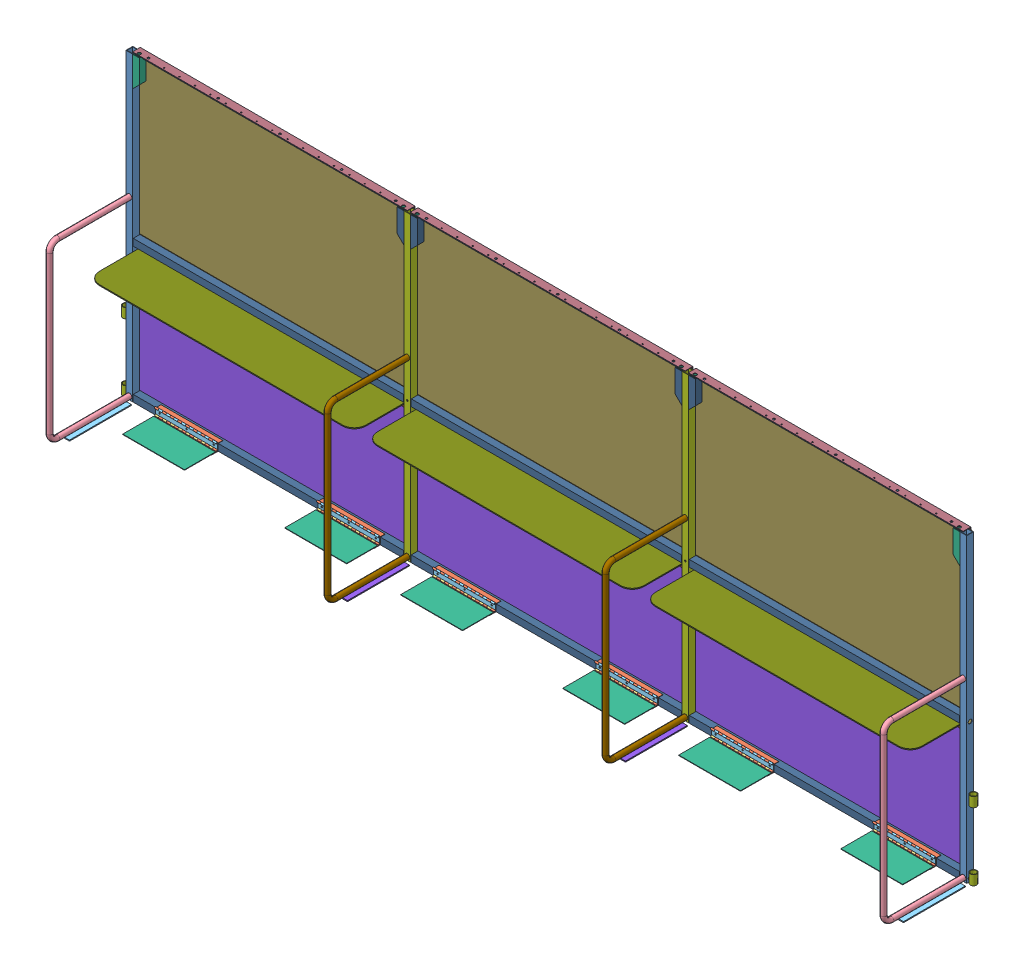
SolidWorks assembly FE-00038-01_ASM, configuration Default. Lengths in mm.
Overall size (5615.18 1984.41 604.9).
184 component instances, 33 part files, 0 mates.
Components (placement in the parent):
- FE-00002-L_ASM-1: FE-00002-L_ASM [Default] at origin size (175.51 1981.23 585.85)
  - FE-00002-05-1: FE-00002-05 [Default] at origin size (44.45 1981.2 44.45)
  - FE-00002-01-1: FE-00002-01 [Default] at (3.175 22.225 -22.225) size (130.18 36.51 36.51)
  - FE-00002-02-1: FE-00002-02 [Default] at (3.175 911.225 -22.225) size (120.65 36.51 36.51)
  - FE-00002-06-1: FE-00002-06 [Default] at (22.225 23.0188 0) x (1 0 0) z (0 0 -1) size (33.4 1168.46 541.4)
  - FE-00002-07-1: FE-00002-07 [Default] at (60.325 6.3182 25.4) x (0 0 1) z (1 0 0) size (406.4 6.35 76.2)
  - FE-00002-03-1: FE-00002-03 [Default] at (44.45 1981.2 0) x (0 0 -1) z (-1 0 0) size (44.45 196.85 44.45)
  - FE-00002-09-1: FE-00002-09 [Default] at (-21.082 31.75 -21.1582) size (42.16 63.5 42.16)
  - FE-00002-09-2: FE-00002-09 [Default] at (-21.082 476.25 -21.1582) size (42.16 63.5 42.16)
- FE-00004_ASM-1: FE-00004_ASM [Default] at (936.625 0 -49.2125) size (1828.8 933.45 374.65)
  - FE-00004-01-1: FE-00004-01 [Default] at origin size (1828.8 914.4 4.76)
  - FE-00004-05-1: FE-00004-05 [Default] at (0 914.4 -4.7625) x (1 0 0) z (0 -1 0) size (1828.8 19.05 19.05)
  - FE-00004-04-1: FE-00004-04 [Default] at (0 911.225 26.9875) size (1778 44.45 44.45)
  - FE-00004-04-2: FE-00004-04 [Default] at (0 22.225 26.9875) size (1778 44.45 44.45)
  - FE-00004-02_ASM-1: FE-00004-02_ASM [Default] at (-647.7 858.139 4.7625) x (-1 0 0) z (0 0 -1) size (406.4 43.56 43.56)
    - FE-00004-02-A-1: FE-00004-02-A [Default] at origin size (406.4 43.56 10.92)
    - FE-00004-02-A-2: FE-00004-02-A [Default] at (0 5.461 -5.461) x (-1 0 0) z (0 1 0) size (406.4 43.56 10.92)
    - FE-00004-02-B-1: FE-00004-02-B [Default] at (0 0 -5.461) size (406.4 6.35 6.35)
  - FE-00004-02_ASM-2: FE-00004-02_ASM [Default] at (647.7 858.139 4.7625) x (-1 0 0) z (0 0 -1) size (406.4 43.56 43.56)
    - FE-00004-02-A-1: FE-00004-02-A [Default] at origin size (406.4 43.56 10.92)
    - FE-00004-02-A-2: FE-00004-02-A [Default] at (0 5.461 -5.461) x (-1 0 0) z (0 1 0) size (406.4 43.56 10.92)
    - FE-00004-02-B-1: FE-00004-02-B [Default] at (0 0 -5.461) size (406.4 6.35 6.35)
  - FE-00004-03_ASM-1: FE-00004-03_ASM [Default] at (0 863.6 10.2235) x (1 0 0) z (0 1 0) size (482.6 43.56 43.56)
    - FE-00004-03-A-1: FE-00004-03-A [Default] at origin size (482.6 43.56 10.92)
    - FE-00004-03-B-1: FE-00004-03-B [Default] at (0 5.461 -5.461) x (-1 0 0) z (0 1 0) size (482.6 43.56 10.92)
    - FE-00004-03-C-1: FE-00004-03-C [Default] at (0 0 -5.461) size (482.6 6.35 6.35)
  - FE-00004-06-1: FE-00004-06 [Default] at (127 863.6 182.5625) size (1752.6 6.35 355.6)
  - FE-00004-09-1: FE-00004-09 [Default] at (-403.9235 787.4 155.2839) x (1 0 0) z (0 -1 0) size (3.18 302.13 152.4)
  - FE-00004-08_ASM-1: FE-00004-08_ASM [Default] at (-400.7485 858.139 179.8901) x (0 0 1) z (-1 0 0) size (203.2 43.56 43.56)
    - FE-00004-08-A-1: FE-00004-08-A [Default] at origin size (203.2 43.56 10.92)
    - FE-00004-08-A-2: FE-00004-08-A [Default] at (0 5.461 -5.461) x (-1 0 0) z (0 1 0) size (203.2 43.56 10.92)
    - FE-00004-08-C-1: FE-00004-08-C [Default] at (0 0 -5.461) size (203.2 6.35 6.35)
  - FE-00004-09-2: FE-00004-09 [Default] at (400.7485 787.4 155.2839) x (1 0 0) z (0 -1 0) size (3.18 302.13 152.4)
  - FE-00004-08_ASM-2: FE-00004-08_ASM [Default] at (400.7485 858.139 179.8901) x (0 0 -1) z (1 0 0) size (203.2 43.56 43.56)
    - FE-00004-08-A-1: FE-00004-08-A [Default] at origin size (203.2 43.56 10.92)
    - FE-00004-08-A-2: FE-00004-08-A [Default] at (0 5.461 -5.461) x (-1 0 0) z (0 1 0) size (203.2 43.56 10.92)
    - FE-00004-08-C-1: FE-00004-08-C [Default] at (0 0 -5.461) size (203.2 6.35 6.35)
  - FE-00004-07_ASM-1: FE-00004-07_ASM [Default] at (-533.4 0 54.6735) x (-1 0 0) z (0 -1 0) size (406.4 73.91 55.37)
    - FE-00004-07-A-1: FE-00004-07-A [Default] at origin size (406.4 43.56 10.92)
    - FE-00004-07-A_AF0-1: FE-00004-07-A_AF0 [Default] at (0 5.461 -5.461) x (-1 0 0) z (0 1 0) size (406.4 43.56 10.92)
    - FE-00004-07-B-1: FE-00004-07-B [Default] at (0 0 -5.461) size (406.4 6.35 6.35)
    - FE-00004-07-A_AF1-1: FE-00004-07-A_AF1 [Default] at (0 3.175 -49.911) x (1 0 0) z (0 1 0) size (406.4 43.56 10.92)
    - FE-00004-07-A-2: FE-00004-07-A [Default] at (0 -2.286 -44.45) x (-1 0 0) z (0 0 1) size (406.4 43.56 10.92)
    - FE-00004-07-B-2: FE-00004-07-B [Default] at (0 -2.286 -49.911) size (406.4 6.35 6.35)
  - FE-00004-07_ASM-2: FE-00004-07_ASM [Default] at (533.4 0 54.6735) x (-1 0 0) z (0 -1 0) size (406.4 73.91 55.37)
    - FE-00004-07-A-1: FE-00004-07-A [Default] at origin size (406.4 43.56 10.92)
    - FE-00004-07-A_AF0-1: FE-00004-07-A_AF0 [Default] at (0 5.461 -5.461) x (-1 0 0) z (0 1 0) size (406.4 43.56 10.92)
    - FE-00004-07-B-1: FE-00004-07-B [Default] at (0 0 -5.461) size (406.4 6.35 6.35)
    - FE-00004-07-A_AF1-1: FE-00004-07-A_AF1 [Default] at (0 3.175 -49.911) x (1 0 0) z (0 1 0) size (406.4 43.56 10.92)
    - FE-00004-07-A-2: FE-00004-07-A [Default] at (0 -2.286 -44.45) x (-1 0 0) z (0 0 1) size (406.4 43.56 10.92)
    - FE-00004-07-B-2: FE-00004-07-B [Default] at (0 -2.286 -49.911) size (406.4 6.35 6.35)
  - FE-00004-10-1: FE-00004-10 [Default] at (-533.4 2.286 168.9735) size (406.4 3.17 203.2)
  - FE-00004-10-2: FE-00004-10 [Default] at (533.4 2.286 168.9735) size (406.4 3.17 203.2)
- FE-00001_ASM-1: FE-00001_ASM [Default] at (1873.25 0 -44.45) x (-1 0 0) z (0 0 -1) size (209.55 1981.2 585.85)
  - FE-00001-05-1: FE-00001-05 [Default] at origin size (44.45 1981.2 44.45)
  - FE-00001-02-1: FE-00001-02 [Default] at (60.325 0 -69.85) x (0 0 -1) z (1 0 0) size (406.4 6.35 76.2)
  - FE-00001-03-1: FE-00001-03 [Default] at (22.225 1158.113 -44.45) size (33.4 1168.46 541.4)
  - FE-00001-01-1: FE-00001-01 [Default] at (44.45 1981.2 0) x (0 0 -1) z (-1 0 0) size (44.45 196.85 44.45)
  - FE-00001-01-2: FE-00001-01 [Default] at (0 1981.2 -44.45) x (0 0 1) z (1 0 0) size (44.45 196.85 44.45)
  - FE-00001-04-1: FE-00001-04 [Default] at (-82.55 22.225 -22.225) size (203.2 36.51 36.51)
  - FE-00001-04-2: FE-00001-04 [Default] at (-76.2 911.225 -22.225) size (203.2 36.51 36.51)
- FE-00004_ASM-2: FE-00004_ASM [Default] at (2765.425 0 -49.2125) size (1828.8 933.45 374.65)
  - FE-00004-01-1: FE-00004-01 [Default] at origin size (1828.8 914.4 4.76)
  - FE-00004-05-1: FE-00004-05 [Default] at (0 914.4 -4.7625) x (1 0 0) z (0 -1 0) size (1828.8 19.05 19.05)
  - FE-00004-04-1: FE-00004-04 [Default] at (0 911.225 26.9875) size (1778 44.45 44.45)
  - FE-00004-04-2: FE-00004-04 [Default] at (0 22.225 26.9875) size (1778 44.45 44.45)
  - FE-00004-02_ASM-1: FE-00004-02_ASM [Default] at (-647.7 858.139 4.7625) x (-1 0 0) z (0 0 -1) size (406.4 43.56 43.56)
    - FE-00004-02-A-1: FE-00004-02-A [Default] at origin size (406.4 43.56 10.92)
    - FE-00004-02-A-2: FE-00004-02-A [Default] at (0 5.461 -5.461) x (-1 0 0) z (0 1 0) size (406.4 43.56 10.92)
    - FE-00004-02-B-1: FE-00004-02-B [Default] at (0 0 -5.461) size (406.4 6.35 6.35)
  - FE-00004-02_ASM-2: FE-00004-02_ASM [Default] at (647.7 858.139 4.7625) x (-1 0 0) z (0 0 -1) size (406.4 43.56 43.56)
    - FE-00004-02-A-1: FE-00004-02-A [Default] at origin size (406.4 43.56 10.92)
    - FE-00004-02-A-2: FE-00004-02-A [Default] at (0 5.461 -5.461) x (-1 0 0) z (0 1 0) size (406.4 43.56 10.92)
    - FE-00004-02-B-1: FE-00004-02-B [Default] at (0 0 -5.461) size (406.4 6.35 6.35)
  - FE-00004-03_ASM-1: FE-00004-03_ASM [Default] at (0 863.6 10.2235) x (1 0 0) z (0 1 0) size (482.6 43.56 43.56)
    - FE-00004-03-A-1: FE-00004-03-A [Default] at origin size (482.6 43.56 10.92)
    - FE-00004-03-B-1: FE-00004-03-B [Default] at (0 5.461 -5.461) x (-1 0 0) z (0 1 0) size (482.6 43.56 10.92)
    - FE-00004-03-C-1: FE-00004-03-C [Default] at (0 0 -5.461) size (482.6 6.35 6.35)
  - FE-00004-06-1: FE-00004-06 [Default] at (127 863.6 182.5625) size (1752.6 6.35 355.6)
  - FE-00004-09-1: FE-00004-09 [Default] at (-403.9235 787.4 155.2839) x (1 0 0) z (0 -1 0) size (3.18 302.13 152.4)
  - FE-00004-08_ASM-1: FE-00004-08_ASM [Default] at (-400.7485 858.139 179.8901) x (0 0 1) z (-1 0 0) size (203.2 43.56 43.56)
    - FE-00004-08-A-1: FE-00004-08-A [Default] at origin size (203.2 43.56 10.92)
    - FE-00004-08-A-2: FE-00004-08-A [Default] at (0 5.461 -5.461) x (-1 0 0) z (0 1 0) size (203.2 43.56 10.92)
    - FE-00004-08-C-1: FE-00004-08-C [Default] at (0 0 -5.461) size (203.2 6.35 6.35)
  - FE-00004-09-2: FE-00004-09 [Default] at (400.7485 787.4 155.2839) x (1 0 0) z (0 -1 0) size (3.18 302.13 152.4)
  - FE-00004-08_ASM-2: FE-00004-08_ASM [Default] at (400.7485 858.139 179.8901) x (0 0 -1) z (1 0 0) size (203.2 43.56 43.56)
    - FE-00004-08-A-1: FE-00004-08-A [Default] at origin size (203.2 43.56 10.92)
    - FE-00004-08-A-2: FE-00004-08-A [Default] at (0 5.461 -5.461) x (-1 0 0) z (0 1 0) size (203.2 43.56 10.92)
    - FE-00004-08-C-1: FE-00004-08-C [Default] at (0 0 -5.461) size (203.2 6.35 6.35)
  - FE-00004-07_ASM-1: FE-00004-07_ASM [Default] at (-533.4 0 54.6735) x (-1 0 0) z (0 -1 0) size (406.4 73.91 55.37)
    - FE-00004-07-A-1: FE-00004-07-A [Default] at origin size (406.4 43.56 10.92)
    - FE-00004-07-A_AF0-1: FE-00004-07-A_AF0 [Default] at (0 5.461 -5.461) x (-1 0 0) z (0 1 0) size (406.4 43.56 10.92)
    - FE-00004-07-B-1: FE-00004-07-B [Default] at (0 0 -5.461) size (406.4 6.35 6.35)
    - FE-00004-07-A_AF1-1: FE-00004-07-A_AF1 [Default] at (0 3.175 -49.911) x (1 0 0) z (0 1 0) size (406.4 43.56 10.92)
    - FE-00004-07-A-2: FE-00004-07-A [Default] at (0 -2.286 -44.45) x (-1 0 0) z (0 0 1) size (406.4 43.56 10.92)
    - FE-00004-07-B-2: FE-00004-07-B [Default] at (0 -2.286 -49.911) size (406.4 6.35 6.35)
  - FE-00004-07_ASM-2: FE-00004-07_ASM [Default] at (533.4 0 54.6735) x (-1 0 0) z (0 -1 0) size (406.4 73.91 55.37)
    - FE-00004-07-A-1: FE-00004-07-A [Default] at origin size (406.4 43.56 10.92)
    - FE-00004-07-A_AF0-1: FE-00004-07-A_AF0 [Default] at (0 5.461 -5.461) x (-1 0 0) z (0 1 0) size (406.4 43.56 10.92)
    - FE-00004-07-B-1: FE-00004-07-B [Default] at (0 0 -5.461) size (406.4 6.35 6.35)
    - FE-00004-07-A_AF1-1: FE-00004-07-A_AF1 [Default] at (0 3.175 -49.911) x (1 0 0) z (0 1 0) size (406.4 43.56 10.92)
    - FE-00004-07-A-2: FE-00004-07-A [Default] at (0 -2.286 -44.45) x (-1 0 0) z (0 0 1) size (406.4 43.56 10.92)
    - FE-00004-07-B-2: FE-00004-07-B [Default] at (0 -2.286 -49.911) size (406.4 6.35 6.35)
  - FE-00004-10-1: FE-00004-10 [Default] at (-533.4 2.286 168.9735) size (406.4 3.17 203.2)
  - FE-00004-10-2: FE-00004-10 [Default] at (533.4 2.286 168.9735) size (406.4 3.17 203.2)
- FE-00001_ASM-2: FE-00001_ASM [Default] at (3702.05 0 -44.45) x (-1 0 0) z (0 0 -1) size (209.55 1981.2 585.85)
  - FE-00001-05-1: FE-00001-05 [Default] at origin size (44.45 1981.2 44.45)
  - FE-00001-02-1: FE-00001-02 [Default] at (60.325 0 -69.85) x (0 0 -1) z (1 0 0) size (406.4 6.35 76.2)
  - FE-00001-03-1: FE-00001-03 [Default] at (22.225 1158.113 -44.45) size (33.4 1168.46 541.4)
  - FE-00001-01-1: FE-00001-01 [Default] at (44.45 1981.2 0) x (0 0 -1) z (-1 0 0) size (44.45 196.85 44.45)
  - FE-00001-01-2: FE-00001-01 [Default] at (0 1981.2 -44.45) x (0 0 1) z (1 0 0) size (44.45 196.85 44.45)
  - FE-00001-04-1: FE-00001-04 [Default] at (-82.55 22.225 -22.225) size (203.2 36.51 36.51)
  - FE-00001-04-2: FE-00001-04 [Default] at (-76.2 911.225 -22.225) size (203.2 36.51 36.51)
- FE-00004_ASM-3: FE-00004_ASM [Default] at (4594.225 0 -49.2125) size (1828.8 933.45 374.65)
  - FE-00004-01-1: FE-00004-01 [Default] at origin size (1828.8 914.4 4.76)
  - FE-00004-05-1: FE-00004-05 [Default] at (0 914.4 -4.7625) x (1 0 0) z (0 -1 0) size (1828.8 19.05 19.05)
  - FE-00004-04-1: FE-00004-04 [Default] at (0 911.225 26.9875) size (1778 44.45 44.45)
  - FE-00004-04-2: FE-00004-04 [Default] at (0 22.225 26.9875) size (1778 44.45 44.45)
  - FE-00004-02_ASM-1: FE-00004-02_ASM [Default] at (-647.7 858.139 4.7625) x (-1 0 0) z (0 0 -1) size (406.4 43.56 43.56)
    - FE-00004-02-A-1: FE-00004-02-A [Default] at origin size (406.4 43.56 10.92)
    - FE-00004-02-A-2: FE-00004-02-A [Default] at (0 5.461 -5.461) x (-1 0 0) z (0 1 0) size (406.4 43.56 10.92)
    - FE-00004-02-B-1: FE-00004-02-B [Default] at (0 0 -5.461) size (406.4 6.35 6.35)
  - FE-00004-02_ASM-2: FE-00004-02_ASM [Default] at (647.7 858.139 4.7625) x (-1 0 0) z (0 0 -1) size (406.4 43.56 43.56)
    - FE-00004-02-A-1: FE-00004-02-A [Default] at origin size (406.4 43.56 10.92)
    - FE-00004-02-A-2: FE-00004-02-A [Default] at (0 5.461 -5.461) x (-1 0 0) z (0 1 0) size (406.4 43.56 10.92)
    - FE-00004-02-B-1: FE-00004-02-B [Default] at (0 0 -5.461) size (406.4 6.35 6.35)
  - FE-00004-03_ASM-1: FE-00004-03_ASM [Default] at (0 863.6 10.2235) x (1 0 0) z (0 1 0) size (482.6 43.56 43.56)
    - FE-00004-03-A-1: FE-00004-03-A [Default] at origin size (482.6 43.56 10.92)
    - FE-00004-03-B-1: FE-00004-03-B [Default] at (0 5.461 -5.461) x (-1 0 0) z (0 1 0) size (482.6 43.56 10.92)
    - FE-00004-03-C-1: FE-00004-03-C [Default] at (0 0 -5.461) size (482.6 6.35 6.35)
  - FE-00004-06-1: FE-00004-06 [Default] at (127 863.6 182.5625) size (1752.6 6.35 355.6)
  - FE-00004-09-1: FE-00004-09 [Default] at (-403.9235 787.4 155.2839) x (1 0 0) z (0 -1 0) size (3.18 302.13 152.4)
  - FE-00004-08_ASM-1: FE-00004-08_ASM [Default] at (-400.7485 858.139 179.8901) x (0 0 1) z (-1 0 0) size (203.2 43.56 43.56)
    - FE-00004-08-A-1: FE-00004-08-A [Default] at origin size (203.2 43.56 10.92)
    - FE-00004-08-A-2: FE-00004-08-A [Default] at (0 5.461 -5.461) x (-1 0 0) z (0 1 0) size (203.2 43.56 10.92)
    - FE-00004-08-C-1: FE-00004-08-C [Default] at (0 0 -5.461) size (203.2 6.35 6.35)
  - FE-00004-09-2: FE-00004-09 [Default] at (400.7485 787.4 155.2839) x (1 0 0) z (0 -1 0) size (3.18 302.13 152.4)
  - FE-00004-08_ASM-2: FE-00004-08_ASM [Default] at (400.7485 858.139 179.8901) x (0 0 -1) z (1 0 0) size (203.2 43.56 43.56)
    - FE-00004-08-A-1: FE-00004-08-A [Default] at origin size (203.2 43.56 10.92)
    - FE-00004-08-A-2: FE-00004-08-A [Default] at (0 5.461 -5.461) x (-1 0 0) z (0 1 0) size (203.2 43.56 10.92)
    - FE-00004-08-C-1: FE-00004-08-C [Default] at (0 0 -5.461) size (203.2 6.35 6.35)
  - FE-00004-07_ASM-1: FE-00004-07_ASM [Default] at (-533.4 0 54.6735) x (-1 0 0) z (0 -1 0) size (406.4 73.91 55.37)
    - FE-00004-07-A-1: FE-00004-07-A [Default] at origin size (406.4 43.56 10.92)
    - FE-00004-07-A_AF0-1: FE-00004-07-A_AF0 [Default] at (0 5.461 -5.461) x (-1 0 0) z (0 1 0) size (406.4 43.56 10.92)
    - FE-00004-07-B-1: FE-00004-07-B [Default] at (0 0 -5.461) size (406.4 6.35 6.35)
    - FE-00004-07-A_AF1-1: FE-00004-07-A_AF1 [Default] at (0 3.175 -49.911) x (1 0 0) z (0 1 0) size (406.4 43.56 10.92)
    - FE-00004-07-A-2: FE-00004-07-A [Default] at (0 -2.286 -44.45) x (-1 0 0) z (0 0 1) size (406.4 43.56 10.92)
    - FE-00004-07-B-2: FE-00004-07-B [Default] at (0 -2.286 -49.911) size (406.4 6.35 6.35)
  - FE-00004-07_ASM-2: FE-00004-07_ASM [Default] at (533.4 0 54.6735) x (-1 0 0) z (0 -1 0) size (406.4 73.91 55.37)
    - FE-00004-07-A-1: FE-00004-07-A [Default] at origin size (406.4 43.56 10.92)
    - FE-00004-07-A_AF0-1: FE-00004-07-A_AF0 [Default] at (0 5.461 -5.461) x (-1 0 0) z (0 1 0) size (406.4 43.56 10.92)
    - FE-00004-07-B-1: FE-00004-07-B [Default] at (0 0 -5.461) size (406.4 6.35 6.35)
    - FE-00004-07-A_AF1-1: FE-00004-07-A_AF1 [Default] at (0 3.175 -49.911) x (1 0 0) z (0 1 0) size (406.4 43.56 10.92)
    - FE-00004-07-A-2: FE-00004-07-A [Default] at (0 -2.286 -44.45) x (-1 0 0) z (0 0 1) size (406.4 43.56 10.92)
    - FE-00004-07-B-2: FE-00004-07-B [Default] at (0 -2.286 -49.911) size (406.4 6.35 6.35)
  - FE-00004-10-1: FE-00004-10 [Default] at (-533.4 2.286 168.9735) size (406.4 3.17 203.2)
  - FE-00004-10-2: FE-00004-10 [Default] at (533.4 2.286 168.9735) size (406.4 3.17 203.2)
- FE-00002-R_ASM-1: FE-00002-R_ASM [Default] at (5530.85 0 -44.45) x (-1 0 0) z (0 0 -1) size (175.51 1981.23 585.85)
  - FE-00002-05-1: FE-00002-05 [Default] at origin size (44.45 1981.2 44.45)
  - FE-00002-01-1: FE-00002-01 [Default] at (3.175 22.225 -22.225) size (130.18 36.51 36.51)
  - FE-00002-02-1: FE-00002-02 [Default] at (3.175 911.225 -22.225) size (120.65 36.51 36.51)
  - FE-00002-06-1: FE-00002-06 [Default] at (22.225 23.0188 -44.45) x (-1 0 0) z (0 0 1) size (33.4 1168.46 541.4)
  - FE-00002-07-1: FE-00002-07 [Default] at (-15.875 -0.0318 -476.25) x (0 0 1) z (-1 0 0) size (406.4 6.35 76.2)
  - FE-00002-03-1: FE-00002-03 [Default] at (44.45 1981.2 0) x (0 0 -1) z (-1 0 0) size (44.45 196.85 44.45)
  - FE-00002-09-1: FE-00002-09 [Default] at (-21.082 31.75 -21.1582) size (42.16 63.5 42.16)
  - FE-00002-09-2: FE-00002-09 [Default] at (-21.082 476.25 -21.1582) size (42.16 63.5 42.16)
- FE-00012-1: FE-00012 [Default] at (3679.825 917.575 -57.15) size (1828.8 1054.1 9.53)
- FE-00012-2: FE-00012 [Default] at (1851.025 917.575 -57.15) size (1828.8 1054.1 9.53)
- FE-00012-3: FE-00012 [Default] at (22.225 917.575 -57.15) size (1828.8 1054.1 9.53)
- FE-00007_ASM-1: FE-00007_ASM [Default] at (937.4187 1984.375 -60.325) x (0 0 1) z (1 0 0) size (56.36 123.83 1808.16)
  - FE-00007-01_AF0-1: FE-00007-01_AF0 [Default] at origin size (50.8 50.8 1808.16)
  - FE-00007-02_AF0-1: FE-00007-02_AF0 [Default] at (12.7 3.175 -2.3813) size (38.1 38.1 1662.11)
  - FE-00007-03-1: FE-00007-03 [Default] at (38.1 123.825 866.775) x (-1 0 0) z (0 1 0) size (36.51 36.51 120.65)
  - FE-00007-03-2: FE-00007-03 [Default] at (38.1 123.825 -871.5375) x (-1 0 0) z (0 1 0) size (36.51 36.51 120.65)
- FE-00007_ASM-2: FE-00007_ASM [Default] at (2764.6312 1984.375 -60.325) x (0 0 1) z (1 0 0) size (56.36 123.83 1808.16)
  - FE-00007-01_AF0-1: FE-00007-01_AF0 [Default] at origin size (50.8 50.8 1808.16)
  - FE-00007-02_AF0-1: FE-00007-02_AF0 [Default] at (12.7 3.175 -2.3813) size (38.1 38.1 1662.11)
  - FE-00007-03-1: FE-00007-03 [Default] at (38.1 123.825 866.775) x (-1 0 0) z (0 1 0) size (36.51 36.51 120.65)
  - FE-00007-03-2: FE-00007-03 [Default] at (38.1 123.825 -871.5375) x (-1 0 0) z (0 1 0) size (36.51 36.51 120.65)
- FE-00007_ASM-3: FE-00007_ASM [Default] at (4593.4312 1984.375 -60.325) x (0 0 1) z (1 0 0) size (56.36 123.83 1808.16)
  - FE-00007-01_AF0-1: FE-00007-01_AF0 [Default] at origin size (50.8 50.8 1808.16)
  - FE-00007-02_AF0-1: FE-00007-02_AF0 [Default] at (12.7 3.175 -2.3813) size (38.1 38.1 1662.11)
  - FE-00007-03-1: FE-00007-03 [Default] at (38.1 123.825 866.775) x (-1 0 0) z (0 1 0) size (36.51 36.51 120.65)
  - FE-00007-03-2: FE-00007-03 [Default] at (38.1 123.825 -871.5375) x (-1 0 0) z (0 1 0) size (36.51 36.51 120.65)
